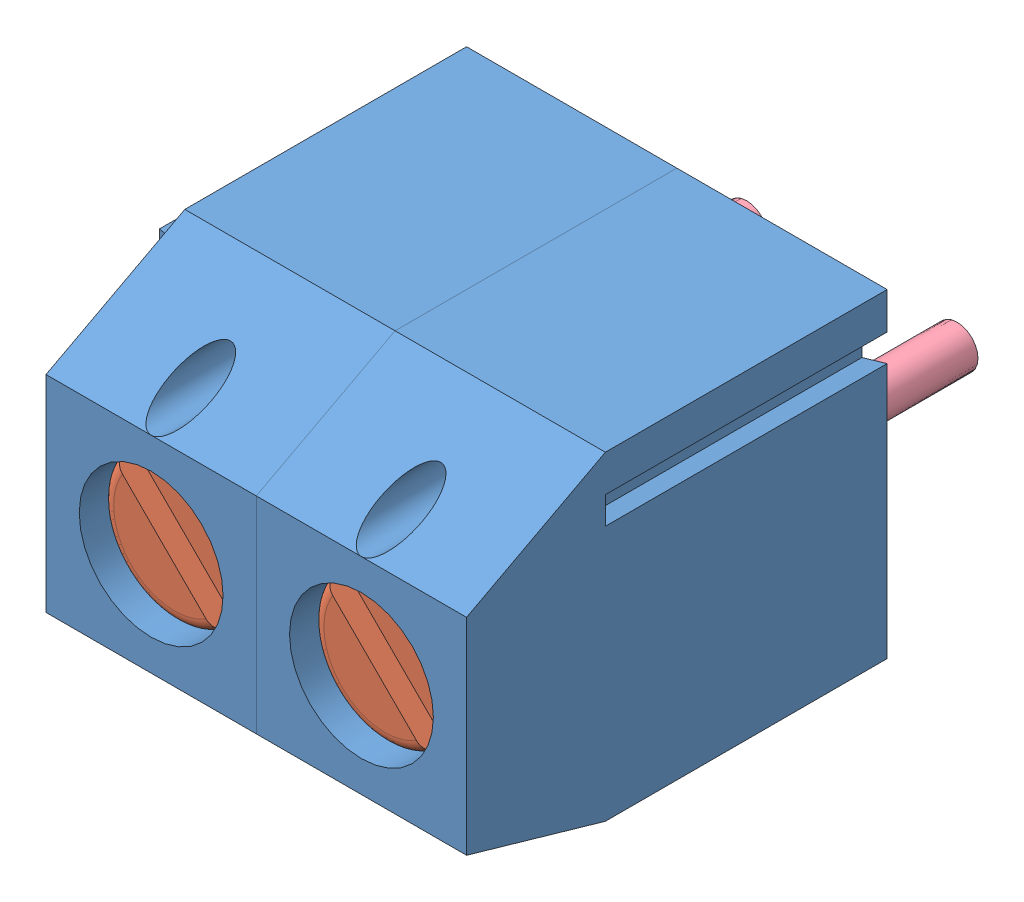
SolidWorks assembly User Library-DG301-5.0-2P12, configuration Default. Lengths in mm.
Overall size (10.6 7.6 14.16).
8 component instances, 4 part files, 6 mates.
Components (placement in the parent):
- User Library-DG301-5.0-2P12_DG301-5.0-1: User Library-DG301-5.0-2P12_DG301-5.0 [Default] at origin size (5.6 7.6 10)
- User Library-DG301-5.0-2P12_DG301-5.0-Sruba-1: User Library-DG301-5.0-2P12_DG301-5.0-Sruba [Default] at (0 0 8) x (-0.707107 -0.707107 0) z (0 0 1) size (3.5 3.5 6.06)
- User Library-DG301-5.0-2P12_DG301-5.0-Blaszka-1: User Library-DG301-5.0-2P12_DG301-5.0-Blaszka [Default] at (0 -0.32 5.57) x (0 1 0) z (0 0 1) size (5.38 3.85 2.68)
- User Library-DG301-5.0-2P12_DG301-5.0-PIN-1: User Library-DG301-5.0-2P12_DG301-5.0-PIN [Default] at (0 -0.3 0.84) size (4 4 9.73)
- User Library-DG301-5.0-2P12_DG301-5.0-2: User Library-DG301-5.0-2P12_DG301-5.0 [Default] at (5 0 0) size (5.6 7.6 10)
- User Library-DG301-5.0-2P12_DG301-5.0-Sruba-2: User Library-DG301-5.0-2P12_DG301-5.0-Sruba [Default] at (5 0 8) x (-0.707107 -0.707107 0) z (0 0 1) size (3.5 3.5 6.06)
- User Library-DG301-5.0-2P12_DG301-5.0-Blaszka-2: User Library-DG301-5.0-2P12_DG301-5.0-Blaszka [Default] at (5 -0.32 5.57) x (0 1 0) z (0 0 1) size (5.38 3.85 2.68)
- User Library-DG301-5.0-2P12_DG301-5.0-PIN-2: User Library-DG301-5.0-2P12_DG301-5.0-PIN [Default] at (5 -0.3 0.84) size (4 4 9.73)
Mates (geometry in assembly coordinates):
- Расстояние1: distance = 1.1 mm: plane of User Library-DG301-5.0-2P12_DG301-5.0-PIN-1 through (-2 -2.3 0.84) normal (0 -1 0); plane of User Library-DG301-5.0-2P12_DG301-5.0-1 through (0 -3.4 6.7) normal (0 -1 0)
- Расстояние3: distance = 0 mm: plane of User Library-DG301-5.0-2P12_DG301-5.0-2 through (5 -3.4 6.7) normal (0 -1 0); plane of User Library-DG301-5.0-2P12_DG301-5.0-1 through (0 -3.4 6.7) normal (0 -1 0)
- Расстояние4: distance = 0 mm: plane of User Library-DG301-5.0-2P12_DG301-5.0-2 through (5 0 0) normal (0 0 -1); plane of User Library-DG301-5.0-2P12_DG301-5.0-1 through (0 0 0) normal (0 0 -1)
- Расстояние5: distance = 1.1 mm: plane of User Library-DG301-5.0-2P12_DG301-5.0-PIN-2 through (3 -2.3 0.84) normal (0 -1 0); plane of User Library-DG301-5.0-2P12_DG301-5.0-2 through (5 -3.4 6.7) normal (0 -1 0)
- Совпадение4: coincident: line of User Library-DG301-5.0-2P12_DG301-5.0-Blaszka-1 through (-1 -2.3 5.47) axis (0 0 -1); plane of User Library-DG301-5.0-2P12_DG301-5.0-PIN-1 through (-2 -2.3 0.84) normal (0 -1 0)
- Совпадение5: coincident: line of User Library-DG301-5.0-2P12_DG301-5.0-Blaszka-2 through (4 -2.3 5.47) axis (0 0 -1); plane of User Library-DG301-5.0-2P12_DG301-5.0-PIN-2 through (3 -2.3 0.84) normal (0 -1 0)
